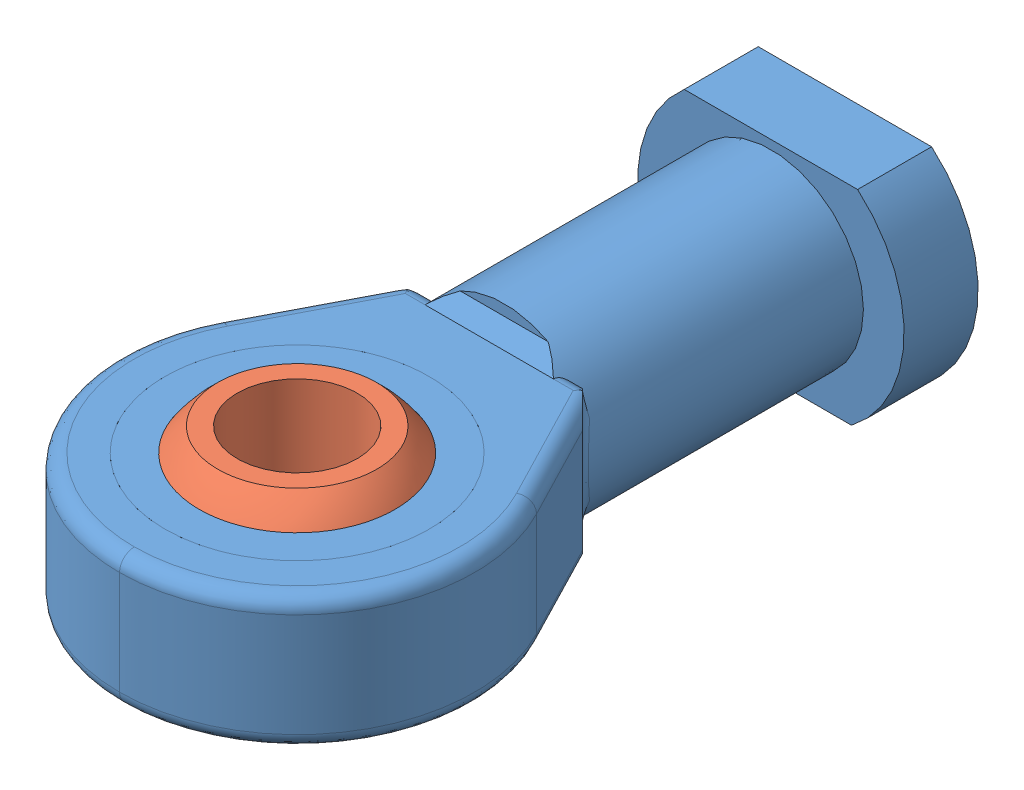
SolidWorks assembly M6 female rod end, configuration Default. Lengths in mm.
Overall size (24 14 49).
2 component instances, 2 part files, 1 mates.
Components (placement in the parent):
- M6 Rod end female-1: M6 Rod end female [Default] at (15.385 25.2771 14.9571) size (24 14 49)
- M6 Rod end ball-1: M6 Rod end ball [Default] at (15.385 25.2771 51.9571) x (0.989698 0.014682 0.142418) z (0.012894 -0.999826 0.013471) size (16 16 12)
Mates (geometry in assembly coordinates):
- Concentric1: concentric: sphere of M6 Rod end female-1; sphere of M6 Rod end ball-1
